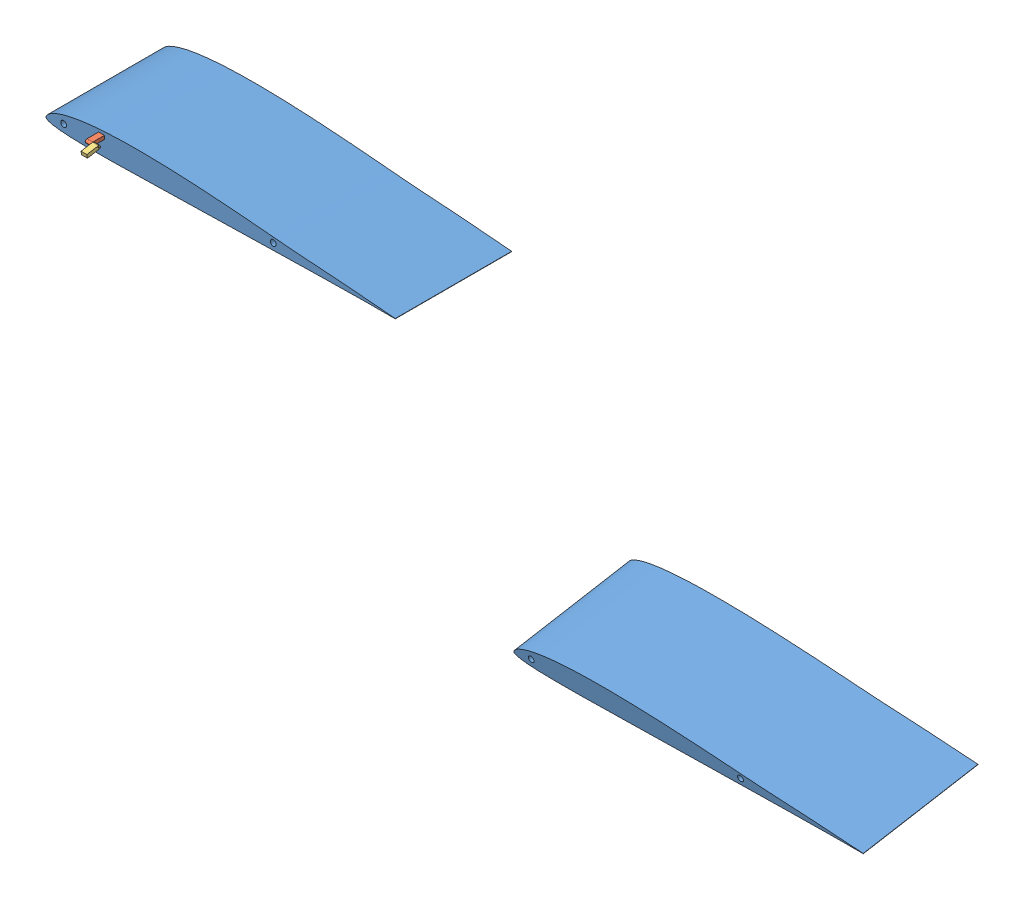
SolidWorks assembly Maple seed assem, configuration Default. Lengths in mm.
Overall size (204.66 28.69 52.41).
4 component instances, 3 part files, 9 mates.
Components (placement in the parent):
- Airfoil segment-1: Airfoil segment [Default] at origin size (76.2 5.05 25.4)
- Airfoil hinge m-1: Airfoil hinge m [Default] at (0 0 13.97) x (0 1 0) z (0 0 -1) size (0.76 2.54 2.92)
- Airfoil hinge f-1: Airfoil hinge f [Default] at (2.54 -0.2169 16.4913) x (0 0.985308 0.170789) z (-1 0 0) size (0.76 2.92 1.27)
- Airfoil segment-2: Airfoil segment [Default] at (128.4509 -21.5281 26.9757) x (1 0 0) z (0 -0.170789 0.985308) size (76.2 5.05 25.4)
Mates (geometry in assembly coordinates):
- Coincident1: coincident aligned: plane of Airfoil segment-1 through (0 0 0) normal (0 0 1)
- Coincident2: coincident aligned: plane of Airfoil segment-1 through (0 0 0) normal (0 1 0)
- Coincident3: coincident aligned: plane of Airfoil segment-1 through (0 0 0) normal (1 0 0)
- Coincident4: coincident anti-aligned: plane of Airfoil segment-1 through (0 0 12.7) normal (0 0 1); plane of Airfoil hinge m-1 through (1.27 0 12.7) normal (0 0 -1)
- Coincident6: coincident aligned: plane of Airfoil hinge m-1 through (0 0 13.97) normal (0 1 0)
- Coincident8: coincident anti-aligned: plane of Airfoil hinge m-1 through (1.27 0 13.97) normal (1 0 0); plane of Airfoil hinge f-1 through (1.27 -0.2169 16.4913) normal (-1 0 0)
- Concentric1: concentric anti-aligned: cylinder of Airfoil hinge m-1 through (2.54 0 15.24) axis (-1 0 0) radius 0.127; cylinder of Airfoil hinge f-1 through (1.27 0 15.24) axis (1 0 0) radius 0.127
- Coincident9: coincident aligned: plane of Airfoil hinge m-1 through (0 0 13.97) normal (1 0 0)
- Coincident10: coincident anti-aligned: plane of Airfoil hinge f-1 through (1.27 -0.4338 17.7427) normal (0 -0.170789 0.985308); plane of Airfoil segment-2 through (128.4509 -19.3591 14.4623) normal (0 0.170789 -0.985308)
